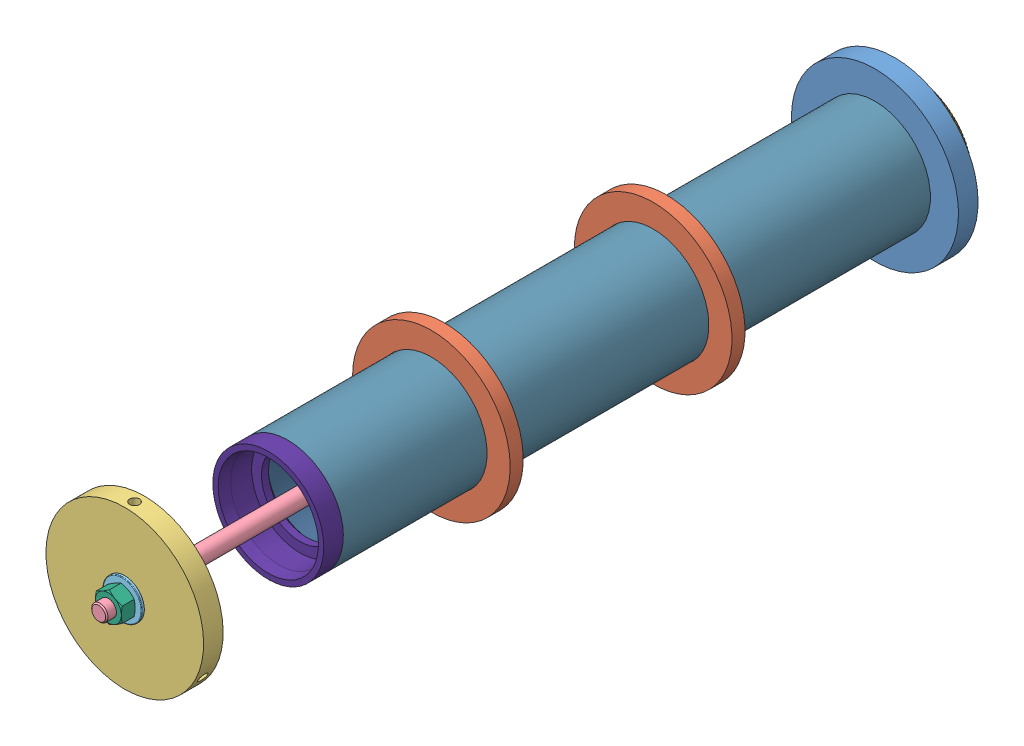
SolidWorks assembly S1B_Propulsion, configuration Default. Lengths in mm.
Overall size (81.28 81.28 396.92).
25 component instances, 17 part files, 56 mates.
Components (placement in the parent):
- S1B_Thrust_Block-1: S1B_Thrust_Block [Default] at (0 0 -9.525) x (1 0 0) z (0 1 0) size (81.28 9.53 81.28)
- S1B_Motor_Casing_Centering_Ring-1: S1B_Motor_Casing_Centering_Ring [Default] at (0 0 209.55) x (0 1 0) z (-1 0 0) size (76.71 6.35 76.71)
- S1B_Motor_Casing_Centering_Ring-2: S1B_Motor_Casing_Centering_Ring [Default] at (0 0 101.6) x (0 1 0) z (-1 0 0) size (76.71 6.35 76.71)
- S1B_Propulsion_Forward_Bulkhead-1: S1B_Propulsion_Forward_Bulkhead [Default] at (0 0 355.6) x (1 0 0) z (0 -1 0) size (76.71 9.53 76.71)
- S1B_Propulsion_Threaded_Rod_90322A682_High-Strength Steel Threaded Rod-1: S1B_Propulsion_Threaded_Rod_90322A682_High-Strength Steel Threaded Rod [90322A682] at (0 0 296.9006) x (0 -1 0) z (0 0 1) size (7.94 7.94 161.85)
- S1B_Propulsion_Threaded_Rod_90107A030_316 Stainless Steel Washer-1: S1B_Propulsion_Threaded_Rod_90107A030_316 Stainless Steel Washer [90107A030] at (0 0 365.76) x (0 1 0) z (0 0 1) size (19.05 19.05 1.27)
- S1B_Propulsion_Threaded_Rod_90107A030_316 Stainless Steel Washer-2: S1B_Propulsion_Threaded_Rod_90107A030_316 Stainless Steel Washer [90107A030] at (0 0 354.965) size (19.05 19.05 1.27)
- S1B_Propulsion_Threaded_Rod_95505A602_Medium-Strength Steel Hex Nut-1: S1B_Propulsion_Threaded_Rod_95505A602_Medium-Strength Steel Hex Nut [95505A602] at (0 0 369.7684) size (12.7 14.66 6.75)
- S1B_Propulsion_Threaded_Rod_95505A602_Medium-Strength Steel Hex Nut-2: S1B_Propulsion_Threaded_Rod_95505A602_Medium-Strength Steel Hex Nut [95505A602] at (0 0 350.9566) size (12.7 14.66 6.75)
- S1B_Motor_and_Motor_Casing-1: S1B_Motor_and_Motor_Casing [Default] at (13.8939 243.3717 -65.3445) x (-1 0 0) z (0 -1 0) size (66.27 314.35 66.27)
  - S1B_Nozzle-1: S1B_Nozzle [Default] at (13.8939 -52.5907 243.3717) x (0.999876 0 -0.015724) z (-0.015724 0 -0.999876) size (50.55 26.47 50.55)
  - S1B_ForwardSealDisk-1: S1B_ForwardSealDisk [Default] at (13.8939 -253.0725 243.3717) x (0.999998 0 0.001834) z (-0.001834 0 0.999998) size (50.4 6.2 50.4)
  - S1B_S1AftClosure-1: S1B_S1AftClosure [Default] at (32.5939 -70.3251 243.3717) size (56.53 20.87 56.51)
  - S1B_CaseSpacer-1: S1B_CaseSpacer [Default] at (13.8939 -342.4625 243.3717) x (0.984366 0 0.176137) z (-0.176137 0 0.984366) size (50.35 83.14 50.35)
  - S1B_FloatingForwardClosure-1: S1B_FloatingForwardClosure [Default] at (13.8939 -253.0725 243.3717) x (0.109892 0 -0.993944) z (-0.993944 0 -0.109892) size (50 36.61 50)
  - S1B_Liner-1: S1B_Liner [Default] at (13.8939 -249.7325 243.3717) x (0.217736 0 0.976008) z (-0.976008 0 0.217736) size (50.7 177.66 50.7)
  - S1B_Grains CAD-1: S1B_Grains CAD [Default] at (13.8939 -246.8682 243.3717) x (0.314643 0 -0.94921) z (0.94921 0 0.314643) size (47 82.35 47)
  - S1B_Casing-2: S1B_Casing [Default] at (13.8939 -351.0945 243.3717) size (54 295.28 54)
  - S1B_Grains CAD-2: S1B_Grains CAD [Default] at (13.8939 -162.9237 243.3717) x (-0.810675 0 -0.585496) z (0.585496 0 -0.810675) size (47 82.35 47)
  - S1B_O-ringL-1: S1B_O-ringL [9452K62] at (13.8939 -67.7195 243.3717) x (0.157366 0 0.98754) z (0 1 0) size (51.1 51.1 3.53)
  - S1B_O-ringL-4: S1B_O-ringL [9452K62] at (13.8939 -254.5725 243.3717) x (0.948867 0 0.315675) z (0 1 0) size (51.1 51.1 3.53)
  - S1B_9452K118_Oil-Resistant Buna-N O-Ring (031)-1: S1B_9452K118_Oil-Resistant Buna-N O-Ring (031) [9452K118] at (13.8939 -248.3325 243.3717) x (0.860014 0 0.510271) z (0 1 0) size (47.73 47.73 1.78)
  - S1B_9452K118_Oil-Resistant Buna-N O-Ring (031)-2: S1B_9452K118_Oil-Resistant Buna-N O-Ring (031) [9452K118] at (13.8939 -79.7075 243.3717) x (-0.052255 0 0.998634) z (0 1 0) size (47.73 47.73 1.78)
  - S1B_9452K118_Oil-Resistant Buna-N O-Ring (031)-3: S1B_9452K118_Oil-Resistant Buna-N O-Ring (031) [9452K118] at (13.8939 -163.8682 243.3717) x (0.996802 0 0.079916) z (0 1 0) size (47.73 47.73 1.78)
  - S1B_S1AftClosure - Copy-1: S1B_S1AftClosure - Copy [Default] at (8.9907 -336.5889 261.4174) x (-0.262202 0 0.965013) z (0.965013 0 0.262202) size (54 20.81 54)
Mates (geometry in assembly coordinates):
- Concentric2: concentric anti-aligned: cylinder of aerotech_54mm_inhouse_nozzle1.step-1 through (0 0 198.3181) axis (0 0 1) radius 19.05; circle of S1_54mm_motor_liner-1
- Concentric3: concentric anti-aligned: cylinder of S1_54mm_motor_casing-1 through (0 0 329.057) axis (0 0 -1) radius 25.527; cylinder of S1_54mm_motor_liner-1 through (0 0 302.006) axis (0 0 1) radius 25.1714
- Concentric6: concentric anti-aligned: cylinder of S1_54mm_motor_casing-1 through (0 0 329.057) axis (0 0 1) radius 26.924; cylinder of S1B_Motor_Casing_Centering_Ring-2 through (0 0 78.8904) axis (0 0 -1) radius 27.1145
- Tangent6: tangent: circle of aerotech_54mm_inhouse_nozzle1.step-1; plane of S1_54mm_motor_liner-1 through (0 0 48.006) normal (0 0 -1)
- Concentric19: concentric anti-aligned: circle of S1_54mm_motor_casing-1; cylinder of orbitalclosure.step-1 through (0 0 33.147) axis (0 0 1) radius 25.146
- Coincident9: coincident anti-aligned: plane of aerotech_54mm_inhouse_nozzle1.step-1 through (0 20.5994 44.831) normal (0 0 -1); plane of orbitalclosure.step-1 through (0 0 44.831) normal (0 0 1)
- Coincident10: coincident anti-aligned: plane of S1_54mm_motor_casing-1 through (0 0 33.147) normal (0 0 -1); plane of orbitalclosure.step-1 through (0 0 33.147) normal (0 0 1)
- Concentric21: concentric anti-aligned: cylinder of Forward Closure-1 through (0 0 313.817) axis (0 0 1) radius 25.0825; cylinder of S1_54mm_motor_casing-1 through (0 0 329.057) axis (0 0 -1) radius 25.527
- Coincident12: coincident anti-aligned: plane of S1_54mm_motor_casing-1 through (0 0 329.057) normal (0 0 1); plane of Forward Closure-1 through (0 0 329.057) normal (0 0 -1)
- Lock1: lock: unknown of S1A_54mm_Motor_Casing-1; unknown of S1B_Motor_Casing_Centering_Ring-2
- Coincident13: coincident anti-aligned: plane of S1A_Aerotech_54mm_Inhouse_Nozzle-1 through (0 0 0) normal (0 0 -1)
- Coincident14: coincident aligned: line of S1A_Aerotech_54mm_Inhouse_Nozzle-1 through (0 0 57.6872) axis (0 0 -1)
- Parallel1: parallel aligned: plane of S1A_Aerotech_54mm_Inhouse_Nozzle-1 through (0 0 39.5051) normal (1 0 0)
- Parallel2: parallel aligned: plane of S1A_54mm_Motor_Casing-1 through (0 0 329.057) normal (1 0 0)
- Parallel3: parallel aligned: plane of S1A_54mm_Motor_Liner-1 through (0 0 302.006) normal (1 0 0)
- Parallel4: parallel aligned: plane of S1B_Thrust_Block-1 through (0 0 -9.525) normal (1 0 0)
- Parallel5: parallel aligned: plane of S1A_Forward_Closure-1 through (0 0 349.885) normal (1 0 0)
- Coincident15: coincident anti-aligned: plane of S1A_Orbital_Closure-1 through (0 0 44.831) normal (-1 0 0)
- Coincident16: coincident aligned: line of S1B_Propulsion_Forward_Bulkhead-1 through (0 0 365.6012) axis (0 0 -1)
- Distance1: distance = 50.8 mm anti-aligned: plane of S1B_Propulsion_Forward_Bulkhead-1 through (0 0 355.6) normal (0 0 -1); plane of S1A_Forward_Closure-1 through (0 0 360.045) normal (0 0 1)
- Parallel6: parallel anti-aligned: plane of S1B_Propulsion_Forward_Bulkhead-1 through (0 0 355.6) normal (0 -1 0)
- Coincident17: coincident aligned: line of S1B_Propulsion_Threaded_Rod_90322A681_High-Strength Steel Threaded Rod-1 through (0 0 675.2824) axis (0 0 -1)
- Parallel7: parallel aligned: plane of S1B_Propulsion_Threaded_Rod_90322A681_High-Strength Steel Threaded Rod-1 through (0 0 340.0024) normal (1 0 0)
- Coincident18: coincident anti-aligned: line of S1A_Propulsion_Threaded_Rod_Nut_95462A510_Medium-Strength Steel Hex Nut-1 through (0 0 369.6498) axis (0 0 1)
- Parallel9: parallel aligned: plane of S1A_Propulsion_Threaded_Rod_Nut_95462A510_Medium-Strength Steel Hex Nut-1 through (0 0 373.3606) normal (1 0 0)
- Parallel12: parallel anti-aligned: plane of S1B_Motor_and_Motor_Casing-1 through (13.8939 243.3717 -65.3445) normal (0 -1 0)
- Coincident34: coincident anti-aligned: plane of S1B_Propulsion_Threaded_Rod_90322A681_High-Strength Steel Threaded Rod-1 through (0 0 298.3) normal (0 0 -1); plane of S1A_Motor_and_Motor_Casing-1/S1A_Forward_Closure-1 through (0 0 298.3) normal (0 0 1)
- Parallel13: parallel aligned: plane of S1B_Thrust_Block-1 through (0 0 -9.525) normal (0 1 0)
- Concentric24: concentric aligned: cylinder of S1B_Motor_Casing_Centering_Ring-1 through (0 0 186.8404) axis (0 0 -1) radius 27.1145
- Coincident33: coincident aligned: plane of S1B_Thrust_Block-1 through (26.924 0 0) normal (0 0 1)
- Distance3: distance = 12.7 mm aligned: plane of S1B_Propulsion_Threaded_Rod_90322A681_High-Strength Steel Threaded Rod-1 through (0 0 381.5949) normal (0 0 1); plane of S1B_Propulsion_Forward_Bulkhead-1 through (0 0 365.125) normal (0 0 1)
- Concentric25: concentric aligned: cylinder of S1B_Motor_Casing_Centering_Ring-2 through (0 0 78.8904) axis (0 0 -1) radius 27.1145
- Distance5: distance = 101.6 mm: plane of assembly through (0 0 0) normal (0 0 1); plane of assembly; plane of S1B_Motor_Casing_Centering_Ring-2 through (0 27.1145 101.6) normal (0 0 -1)
- Distance6: distance = 101.6 mm anti-aligned: plane of S1B_Motor_Casing_Centering_Ring-1 through (0 27.1145 209.55) normal (0 0 -1); plane of S1B_Motor_Casing_Centering_Ring-2 through (0 27.1145 107.95) normal (0 0 1)
- Parallel14: parallel aligned: plane of S1B_Motor_Casing_Centering_Ring-1 through (0 0 209.55) normal (0 1 0)
- Parallel15: parallel aligned: plane of S1B_Motor_Casing_Centering_Ring-2 through (0 0 101.6) normal (0 1 0)
- Concentric26: concentric aligned: cylinder of S1B_Thrust_Block-1 through (0 0 -32.2346) axis (0 0 -1) radius 26.924; cylinder of S1B_Motor_and_Motor_Casing-1/S1B_Casing-1 through (0 0 285.75) axis (0 0 -1) radius 27
- Coincident35: coincident aligned: line of S1B_Propulsion_Threaded_Rod_90322A682_High-Strength Steel Threaded Rod-1 through (0 0 352.7806) axis (0 0 -1)
- Distance9: distance = 12.7 mm aligned: plane of S1B_Propulsion_Threaded_Rod_90322A682_High-Strength Steel Threaded Rod-1 through (0 0 377.825) normal (0 0 1); plane of S1B_Propulsion_Forward_Bulkhead-1 through (0 0 365.125) normal (0 0 1)
- Coincident36: coincident aligned: line of S1B_Propulsion_Threaded_Rod_90322A682_High-Strength Steel Threaded Rod-1 through (0 0 352.7806) axis (0 0 -1)
- Coincident37: coincident anti-aligned: plane of S1B_Propulsion_Forward_Bulkhead-1 through (0 0 365.125) normal (0 0 1); plane of S1B_Propulsion_Threaded_Rod_90107A030_316 Stainless Steel Washer-1 through (0 0 365.125) normal (0 0 -1)
- Coincident38: coincident anti-aligned: plane of S1B_Propulsion_Forward_Bulkhead-1 through (0 0 355.6) normal (0 0 -1); plane of S1B_Propulsion_Threaded_Rod_90107A030_316 Stainless Steel Washer-2 through (0 0 355.6) normal (0 0 1)
- Coincident39: coincident anti-aligned: line of S1B_Propulsion_Threaded_Rod_90107A030_316 Stainless Steel Washer-2 through (0 0 354.2665) axis (0 0 1)
- Coincident40: coincident anti-aligned: line of S1B_Propulsion_Threaded_Rod_90107A030_316 Stainless Steel Washer-1 through (0 0 365.0615) axis (0 0 1)
- Coincident41: coincident aligned: line of S1B_Propulsion_Threaded_Rod_95505A602_Medium-Strength Steel Hex Nut-1 through (0 0 373.4792) axis (0 0 -1)
- Coincident42: coincident anti-aligned: plane of S1B_Propulsion_Threaded_Rod_90107A030_316 Stainless Steel Washer-1 through (0 0 366.395) normal (0 0 1); plane of S1B_Propulsion_Threaded_Rod_95505A602_Medium-Strength Steel Hex Nut-1 through (-6.35 3.6662 366.395) normal (0 0 -1)
- Coincident43: coincident anti-aligned: plane of S1B_Propulsion_Threaded_Rod_90107A030_316 Stainless Steel Washer-2 through (0 0 354.33) normal (0 0 -1); plane of S1B_Propulsion_Threaded_Rod_95505A602_Medium-Strength Steel Hex Nut-2 through (-6.35 3.6662 354.33) normal (0 0 1)
- Coincident44: coincident aligned: line of S1B_Propulsion_Threaded_Rod_95505A602_Medium-Strength Steel Hex Nut-2 through (0 0 354.6673) axis (0 0 -1)
- Parallel16: parallel aligned: plane of S1B_Propulsion_Threaded_Rod_90322A682_High-Strength Steel Threaded Rod-1 through (0 0 296.9006) normal (1 0 0)
- Parallel17: parallel anti-aligned: plane of S1B_Propulsion_Threaded_Rod_90107A030_316 Stainless Steel Washer-1 through (0 0 365.76) normal (-1 0 0)
- Parallel18: parallel aligned: plane of S1B_Propulsion_Threaded_Rod_90107A030_316 Stainless Steel Washer-2 through (0 0 354.965) normal (1 0 0)
- Parallel19: parallel aligned: plane of S1B_Propulsion_Threaded_Rod_95505A602_Medium-Strength Steel Hex Nut-1 through (0 0 369.7684) normal (1 0 0)
- Parallel20: parallel aligned: plane of S1B_Propulsion_Threaded_Rod_95505A602_Medium-Strength Steel Hex Nut-2 through (0 0 350.9566) normal (1 0 0)
- Coincident46: coincident anti-aligned: line of S1B_Motor_and_Motor_Casing-1 through (0 0 -9.525) axis (0 0 1)
- Coincident47: coincident anti-aligned: plane of S1B_Thrust_Block-1 through (26.924 0 -9.525) normal (0 0 -1); plane of S1B_Motor_and_Motor_Casing-1/S1B_S1AftClosure-1 through (-18.7 0 -9.525) normal (0 0 1)
- Distance10: distance = 139.7 mm anti-aligned: plane of S1B_Propulsion_Forward_Bulkhead-1 through (0 0 355.6) normal (0 0 -1); plane of S1B_Motor_Casing_Centering_Ring-1 through (0 27.1145 215.9) normal (0 0 1)
